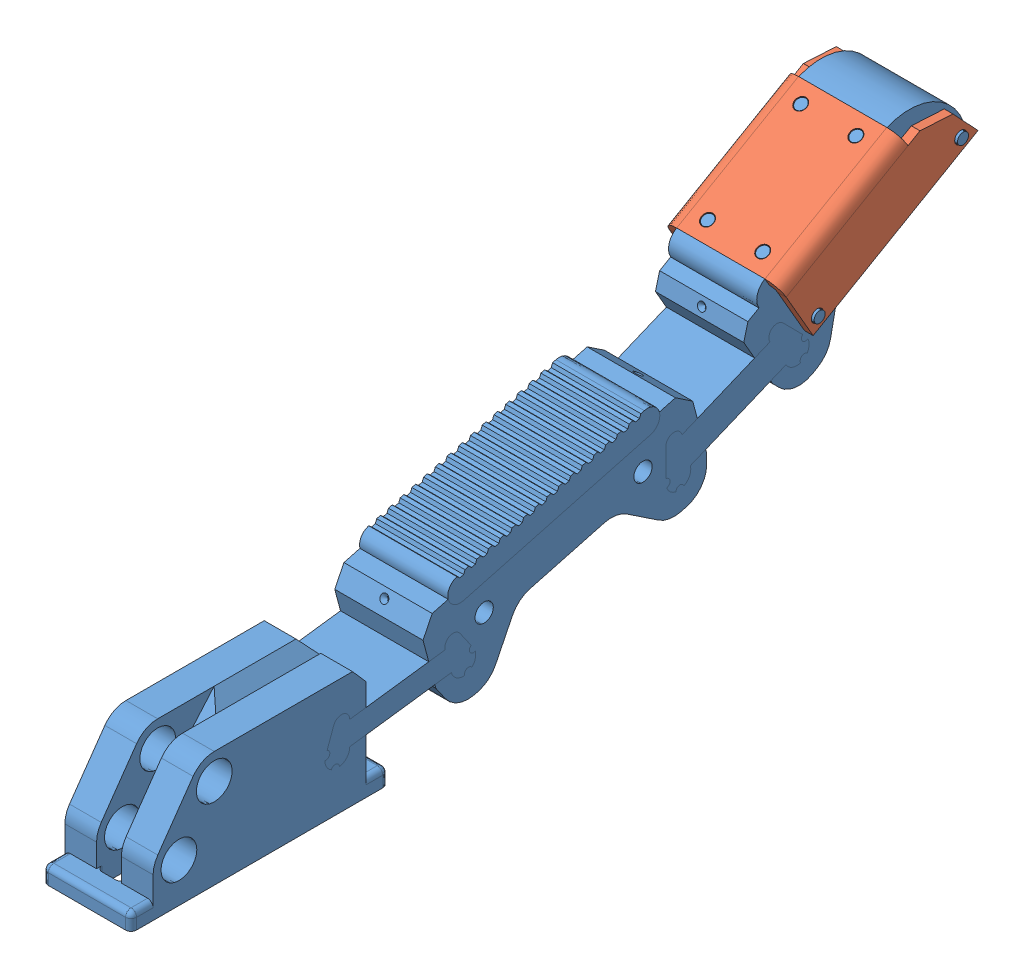
SolidWorks assembly finger_board_asm, configuration Default. Lengths in mm.
Overall size (22 62.51 150.94).
4 component instances, 3 part files, 7 mates.
Components (placement in the parent):
- finger_ff_t-1: finger_ff_t [Default] at (33.7741 50.5333 146.9294) size (19 58.78 150.92)
- pcb_outline-1: pcb_outline [Default] at (33.7741 88.0207 53.9948) x (1 0 0) z (0 0.5 -0.866025) size (21.14 12.34 34.5)
- pcb_peg-1: pcb_peg [Default] at (28.7741 75.093 58.9032) x (0 -0.777632 -0.62872) z (0 0.62872 -0.777632) size (2 6 2)
- pcb_peg-2: pcb_peg [Default] at (28.7741 90.093 32.9224) x (0 0.393851 0.919174) z (0 -0.919174 0.393851) size (2 6 2)
Mates (geometry in assembly coordinates):
- Coincident1: coincident anti-aligned: plane of finger_ff_t-1 through (25.7741 94.3957 42.953) normal (0 0.866025 0.5); plane of pcb_outline-1 through (33.7741 88.0207 53.9948) normal (0 -0.866025 -0.5)
- Coincident6: coincident anti-aligned: plane of finger_ff_t-1 through (28.7741 90.093 32.9224) normal (-1 0 0); plane of pcb_peg-1 through (28.7741 75.093 58.9032) normal (1 0 0)
- Coincident7: coincident anti-aligned: plane of finger_ff_t-1 through (28.7741 75.093 58.9032) normal (-1 0 0); plane of pcb_peg-2 through (28.7741 90.093 32.9224) normal (1 0 0)
- Concentric8: concentric aligned: circle of finger_ff_t-1; circle of pcb_peg-2
- Concentric9: concentric aligned: circle of finger_ff_t-1; circle of pcb_peg-1
- Concentric13: concentric anti-aligned: circle of finger_ff_t-1; circle of pcb_outline-1
- Concentric14: concentric anti-aligned: circle of finger_ff_t-1; circle of pcb_outline-1
